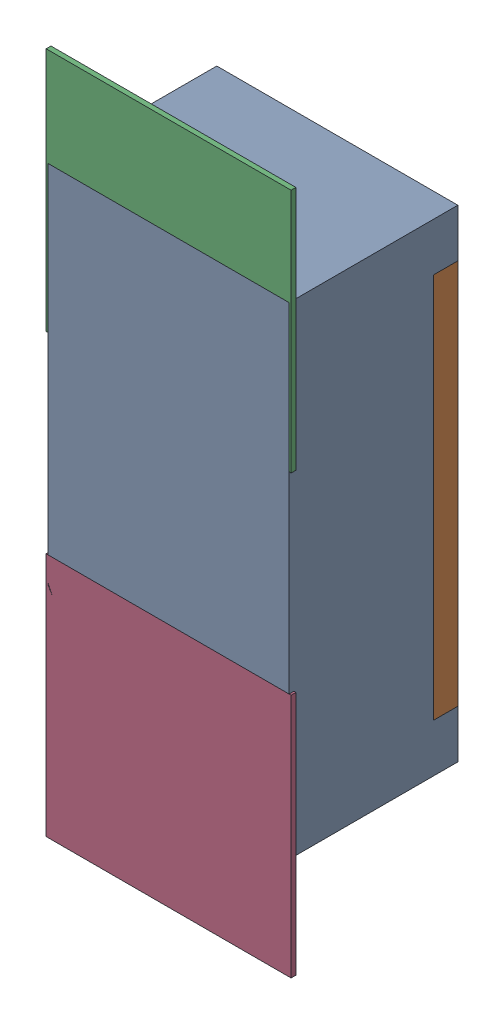
SolidWorks assembly R32, configuration Défaut. Lengths in mm.
Overall size (0.51 1.42 0.35).
5 component instances, 2 part files, 0 mates.
Components (placement in the parent):
- R0402-1: R0402 [Défaut] at (19.8373 -14.7122 -2.0818) x (0 1 0) z (0 0 -1) size (1 0.5 0.35)
- 6504207776-1: 6504207776 [Défaut] at (19.8374 -14.2622 -2.0918) size (0.51 0.51 0.01)
  - Extruded-1: Extruded [Défaut] at origin size (0.51 0.51 0.01)
- 6504207776-2: 6504207776 [Défaut] at (19.8374 -15.1693 -2.0918) size (0.51 0.51 0.01)
  - Extruded-1: Extruded [Défaut] at origin size (0.51 0.51 0.01)
